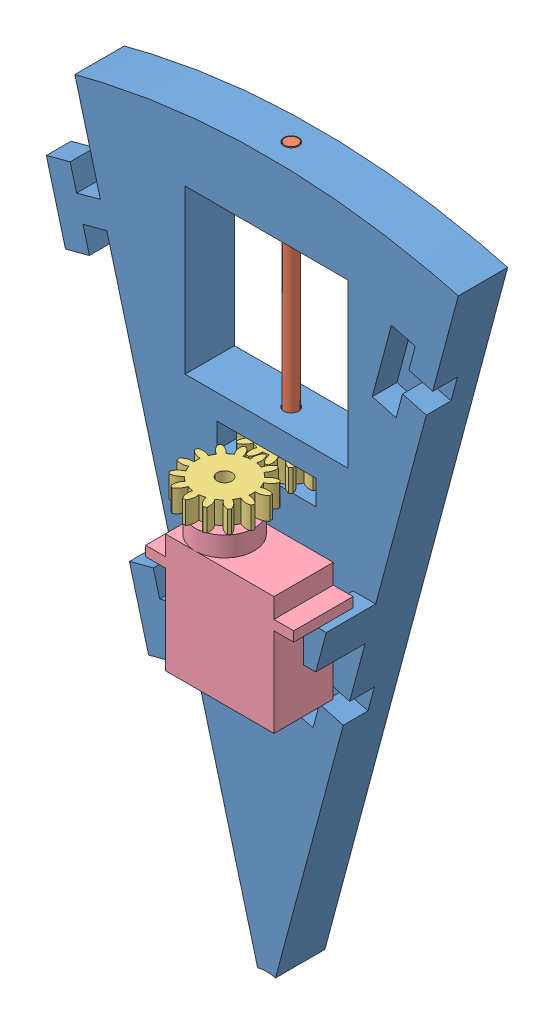
SolidWorks assembly sihverplaat_sektor, configuration Default. Lengths in mm.
Overall size (83.42 143.29 33.73).
5 component instances, 4 part files, 10 mates.
Components (placement in the parent):
- sihverplaat_servo-1: sihverplaat_servo [Default] at (7.1676 178.6045 270.754) size (83.42 143.29 20)
- numbriplaat_shaft-1: numbriplaat_shaft [Default] at (7.1676 268.6607 270.754) size (2.6 60 2.6)
- spur gear_am-6: spur gear_am [Metric - Spur gear 1M 14T 14.5PA 4.5mmFW ---S14N75H50L3N] at (7.1676 272.6045 270.754) x (0 1 0) z (0.994793 0 -0.101917) size (4.5 15.72 16)
- spur gear_am-8: spur gear_am [Metric - Spur gear 1M 14T 14.5PA 4.5mmFW ---S14N75H50L3N] at (7.6676 277.1045 284.754) x (0 -1 0) z (-0.79797 0 0.602697) size (4.5 15.72 16)
- servo-1: servo [Default] at (12.6676 255.1045 278.754) size (30 31 12)
Mates (geometry in assembly coordinates):
- Concentric1: concentric aligned: cylinder of sihverplaat_servo-1 through (7.1676 273.6045 270.754) axis (0 1 0) radius 1.5; circle of numbriplaat_shaft-1
- Concentric6: concentric anti-aligned: cylinder of numbriplaat_shaft-1 through (7.1676 328.6607 270.754) axis (0 -1 0) radius 1.3; circle of spur gear_am-6
- Coincident2: coincident anti-aligned: plane of sihverplaat_servo-1 through (17.1676 277.1045 275.755) normal (0 -1 0); plane of spur gear_am-6 through (7.1676 277.1045 270.754) normal (0 1 0)
- Parallel2: parallel anti-aligned: plane of spur gear_am-6 through (7.1676 277.1045 270.754) normal (0 1 0); plane of spur gear_am-8 through (7.6676 272.6045 284.754) normal (0 -1 0)
- Coincident5: coincident anti-aligned: plane of sihverplaat_servo-1 through (17.1676 277.1045 275.755) normal (0 -1 0); plane of spur gear_am-8 through (7.6676 277.1045 284.754) normal (0 1 0)
- Concentric7: concentric anti-aligned: circle of spur gear_am-8; circle of servo-1
- Distance1: distance = 3 mm anti-aligned: plane of sihverplaat_servo-1 through (7.1676 178.6045 275.754) normal (0 0 1); plane of servo-1 through (12.6676 255.1045 278.754) normal (0 0 -1)
- Distance2: distance = 11 mm anti-aligned: plane of sihverplaat_servo-1 through (-9.3324 282.1045 275.754) normal (1 0 0); plane of servo-1 through (1.6676 243.1045 290.754) normal (-1 0 0)
- GearMate3: gear = 14 : 14 mm: circle of spur gear_am-6; circle of spur gear_am-8
- Coincident6: coincident anti-aligned: plane of sihverplaat_servo-1 through (7.1676 261.1045 285.754) normal (0 1 0); plane of servo-1 through (27.6676 261.1045 278.754) normal (0 -1 0)
